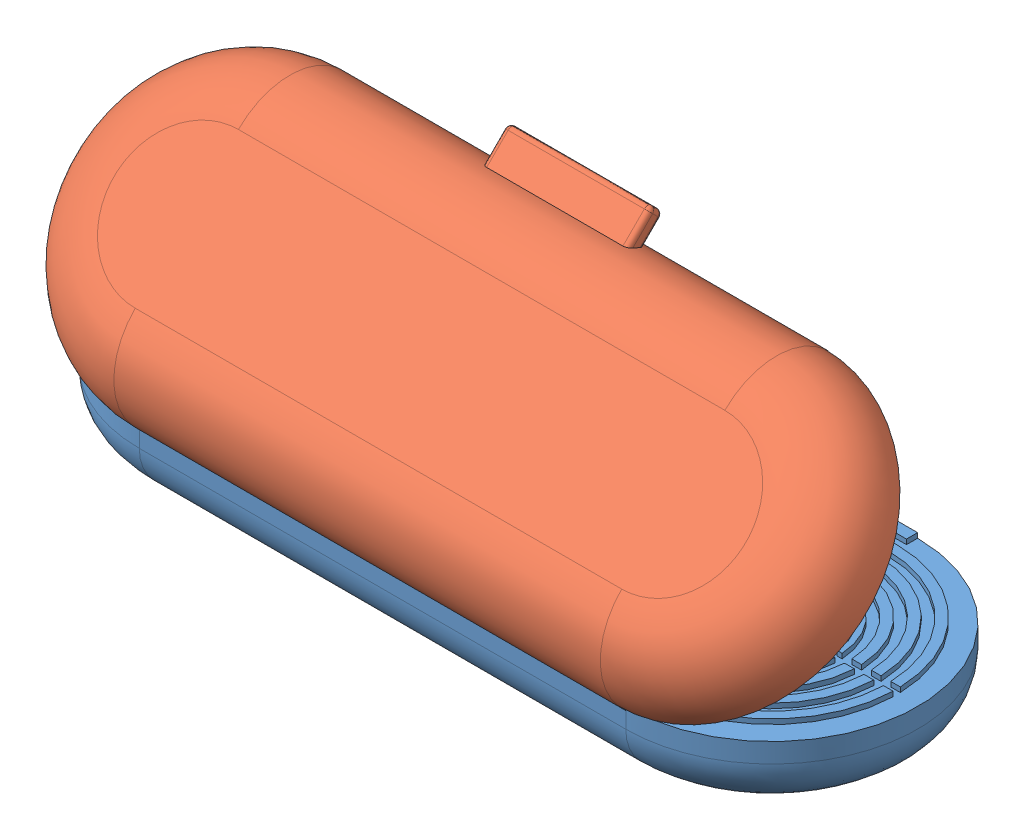
SolidWorks assembly Assem1, configuration Default. Lengths in mm.
Overall size (160 71.08 71.45).
2 component instances, 2 part files, 3 mates.
Components (placement in the parent):
- tostijzer onderkant-1: tostijzer onderkant [Default] at origin size (160 15.57 60.84)
- tostiijzer bovenkant-1: tostiijzer bovenkant [Default] at (0 35.3717 9.6283) x (-1 0 0) z (0 0.707107 -0.707107) size (159.93 15 65.5)
Mates (geometry in assembly coordinates):
- Coincident1: coincident: plane of tostijzer onderkant-1 through (0 22.5 22.5) normal (0 0.707107 0.707107); plane of tostiijzer bovenkant-1 through (0 35.3717 9.6283) normal (0 -0.707107 -0.707107)
- Coincident2: coincident: line of tostijzer onderkant-1 through (0 14.1585 30.8415) axis (1 0 0); line of tostiijzer bovenkant-1 through (0 14.1585 30.8415) axis (1 0 0)
- Coincident3: coincident aligned: line of tostijzer onderkant-1 through (100 14.1585 30.8415) axis (0 0.707107 -0.707107); line of tostiijzer bovenkant-1 through (100 14.1585 30.8415) axis (0 0.707107 -0.707107)
